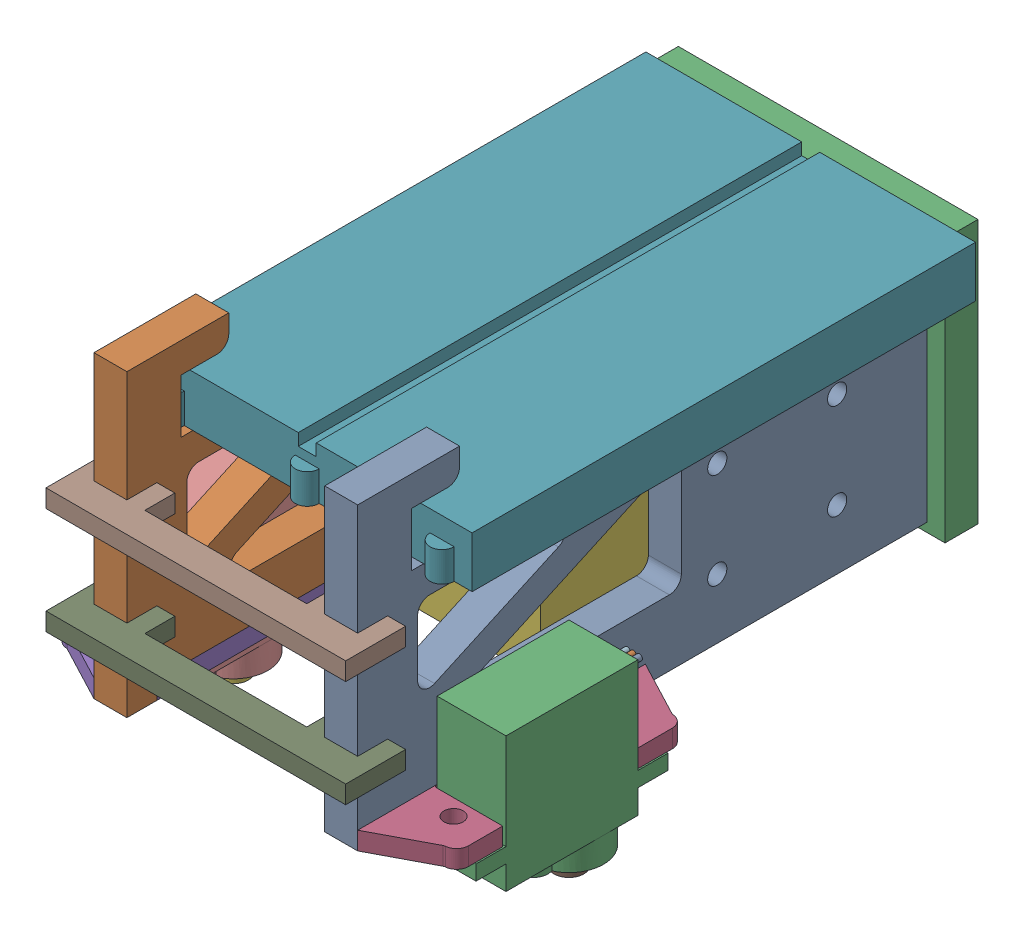
SolidWorks assembly flag-robot, configuration ﾃﾞﾌｫﾙﾄ. Lengths in mm.
Overall size (67.5 63.7 105.5).
9 component instances, 6 part files, 20 mates.
Components (placement in the parent):
- flag-robot_base-frame-1: flag-robot_base-frame [ﾃﾞﾌｫﾙﾄ] at (2.3196 1.1032 50.25) size (50 51.5 100.5)
- flag-robot_servo-mount-1: flag-robot_servo-mount [ﾃﾞﾌｫﾙﾄ] at (18.8196 -14.3968 126.75) x (1 0 0) z (0 -1 0) size (17 48 3)
- flag-robot_servo-mount-2: flag-robot_servo-mount [ﾃﾞﾌｫﾙﾄ] at (-14.1804 -17.3968 126.75) x (-1 0 0) z (0 1 0) size (17 48 3)
- servo_sg-90-1: servo_sg-90 [ﾃﾞﾌｫﾙﾄ] at (-31.4304 -1.3968 137.75) x (0 0 -1) z (0 -1 0) size (32 11.5 29.7)
- servo_sg-90-2: servo_sg-90 [ﾃﾞﾌｫﾙﾄ] at (24.5696 -1.3968 137.75) x (0 0 -1) z (0 -1 0) size (32 11.5 29.7)
- battery_6V-battery-box-2x2-1: battery_6V-battery-box-2x2 [ﾃﾞﾌｫﾙﾄ] at (1.8196 1.6032 55.75) size (32 32 63)
- circuit_bread-board-55x84-1: circuit_bread-board-55x84 [ﾃﾞﾌｫﾙﾄ] at (4.9095 18.6032 97.75) x (0 0 -1) z (0 1 0) size (86 57 8.5)
- flag-robot_frame-joint-1: flag-robot_frame-joint [ﾃﾞﾌｫﾙﾄ] at (-19.6804 14.0712 145.75) x (1 0 0) z (0 -1 0) size (50 10 3)
- flag-robot_frame-joint-2: flag-robot_frame-joint [ﾃﾞﾌｫﾙﾄ] at (-19.6804 -3.7299 145.75) x (1 0 0) z (0 -1 0) size (50 10 3)
Mates (geometry in assembly coordinates):
- 一致2: coincident anti-aligned: plane of flag-robot_base-frame-1 through (2.3196 -14.3968 50.25) normal (0 -1 0); plane of flag-robot_servo-mount-2 through (-14.1804 -14.3968 126.75) normal (0 1 0)
- 同心円7: concentric aligned: cylinder of flag-robot_servo-mount-2 through (-25.6804 -14.3968 140.75) axis (0 -1 0) radius 1.6; cylinder of servo_sg-90-1 through (-25.6804 -1.3968 140.75) axis (0 -1 0) radius 1.5
- 同心円8: concentric aligned: cylinder of flag-robot_servo-mount-2 through (-25.6804 -14.3968 112.75) axis (0 -1 0) radius 1.6; cylinder of servo_sg-90-1 through (-25.6804 -1.3968 112.75) axis (0 -1 0) radius 1.5
- 一致3: coincident anti-aligned: plane of flag-robot_servo-mount-2 through (-14.1804 -17.3968 126.75) normal (0 -1 0); plane of servo_sg-90-1 through (-31.4304 -17.3968 137.75) normal (0 1 0)
- 同心円9: concentric anti-aligned: cylinder of flag-robot_servo-mount-1 through (30.3196 -17.3968 140.75) axis (0 1 0) radius 1.6; cylinder of servo_sg-90-2 through (30.3196 -1.3968 140.75) axis (0 -1 0) radius 1.5
- 一致4: coincident anti-aligned: plane of flag-robot_servo-mount-1 through (18.8196 -17.3968 126.75) normal (0 -1 0); plane of servo_sg-90-2 through (24.5696 -17.3968 137.75) normal (0 1 0)
- 同心円10: concentric anti-aligned: cylinder of flag-robot_servo-mount-1 through (30.3196 -17.3968 112.75) axis (0 1 0) radius 1.6; cylinder of servo_sg-90-2 through (30.3196 -1.3968 112.75) axis (0 -1 0) radius 1.5
- 一致9: coincident anti-aligned: plane of flag-robot_servo-mount-2 through (-14.1804 -14.3968 126.75) normal (0 1 0); plane of battery_6V-battery-box-2x2-1 through (17.8196 -14.3968 113.75) normal (0 -1 0)
- 一致10: coincident anti-aligned: plane of flag-robot_base-frame-1 through (2.3196 1.1032 55.75) normal (0 0 1); plane of battery_6V-battery-box-2x2-1 through (1.8196 1.6032 55.75) normal (0 0 -1)
- 一致11: coincident anti-aligned: plane of flag-robot_base-frame-1 through (-14.1804 1.1032 50.25) normal (1 0 0); plane of battery_6V-battery-box-2x2-1 through (-14.1804 17.6032 113.75) normal (-1 0 0)
- 一致12: coincident anti-aligned: plane of flag-robot_base-frame-1 through (-19.6804 18.6032 55.75) normal (0 1 0); plane of circuit_bread-board-55x84-1 through (4.9095 18.6032 97.75) normal (0 -1 0)
- 平行2: parallel aligned: plane of flag-robot_base-frame-1 through (-19.6804 1.1032 50.25) normal (-1 0 0); plane of circuit_bread-board-55x84-1 through (-22.5905 27.1032 97.75) normal (-1 0 0)
- 一致13: coincident anti-aligned: plane of flag-robot_base-frame-1 through (2.3196 1.1032 55.75) normal (0 0 1); plane of circuit_bread-board-55x84-1 through (4.9095 27.1032 55.75) normal (0 0 -1)
- 一致15: coincident anti-aligned: plane of flag-robot_base-frame-1 through (-19.6804 -14.3968 145.75) normal (0 0 -1); plane of flag-robot_servo-mount-2 through (-14.1804 -14.3968 145.75) normal (0 0 1)
- 一致16: coincident anti-aligned: plane of flag-robot_base-frame-1 through (-19.6804 1.1032 50.25) normal (-1 0 0); plane of flag-robot_servo-mount-2 through (-19.6804 -28.1322 145.75) normal (1 0 0)
- 一致17: coincident anti-aligned: plane of flag-robot_base-frame-1 through (24.3196 1.1032 50.25) normal (1 0 0); plane of flag-robot_servo-mount-1 through (24.3196 -3.6613 145.75) normal (-1 0 0)
- 一致18: coincident anti-aligned: plane of flag-robot_base-frame-1 through (-19.6804 1.1032 50.25) normal (-1 0 0); plane of flag-robot_frame-joint-1 through (-19.6804 5.937 150.75) normal (1 0 0)
- 一致19: coincident anti-aligned: plane of flag-robot_base-frame-1 through (-19.6804 18.6032 150.75) normal (0 0 1); plane of flag-robot_frame-joint-1 through (15.8196 5.937 150.75) normal (0 0 -1)
- 一致20: coincident: plane of flag-robot_base-frame-1 through (-14.1804 1.1032 50.25) normal (1 0 0); plane of flag-robot_frame-joint-2 through (-14.1804 -6.7299 145.75) normal (-1 0 0)
- 一致21: coincident anti-aligned: plane of flag-robot_base-frame-1 through (-19.6804 18.6032 150.75) normal (0 0 1); plane of flag-robot_frame-joint-2 through (15.8196 -6.7299 150.75) normal (0 0 -1)
